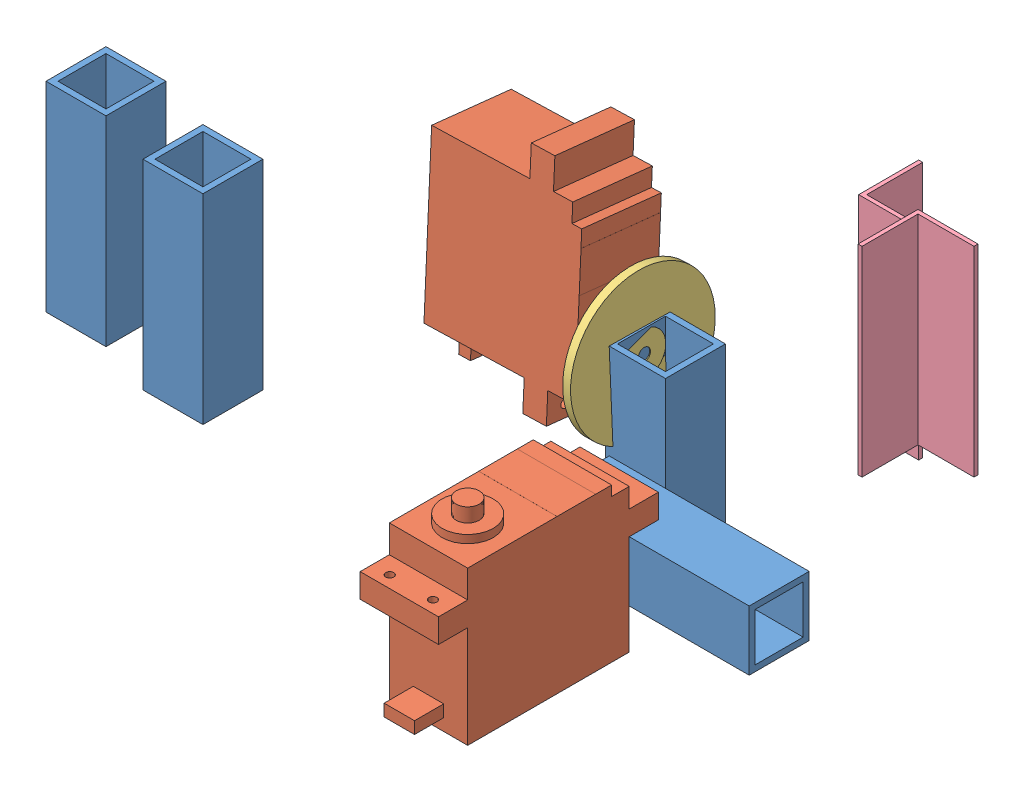
SolidWorks assembly 刀2, configuration ﾃﾞﾌｫﾙﾄ. Lengths in mm.
Overall size (157.88 100.48 102.11).
9 component instances, 4 part files, 4 mates.
Components (placement in the parent):
- 角_15_15_1.5-1: 角_15_15_1.5 [ﾃﾞﾌｫﾙﾄ] at (26.7735 11.274 48.4518) x (0 -1 0) z (-1 0 0) size (15 15 50)
- サーボ_MG995-1: サーボ_MG995 [ﾃﾞﾌｫﾙﾄ] at (12.6341 -6.7159 76.1612) x (-1 0 0) z (0 1 0) size (19.6 55 43.9)
- サーボ_MG995-2: サーボ_MG995 [ﾃﾞﾌｫﾙﾄ] at (-68.1766 42.576 5.5952) x (-0.019684 0.089439 0.995798) z (0.998898 0.044214 0.015775) size (19.6 55 43.9)
- サーボ_円盤-1: サーボ_円盤 [ﾃﾞﾌｫﾙﾄ] at (-25.1765 36.2069 32.7902) x (0.025317 -0.224419 -0.974164) z (0.998898 0.044214 0.015775) size (35.6 35.6 5.1)
- 角_15_15_1.5-2: 角_15_15_1.5 [ﾃﾞﾌｫﾙﾄ] at (-81.3631 24.7489 83.9472) x (-1 0 0) z (0 1 0) size (15 15 50)
- 角_15_15_1.5-3: 角_15_15_1.5 [ﾃﾞﾌｫﾙﾄ] at (-98.939 36.1769 90.6218) x (-1 0 0) z (0 1 0) size (15 15 50)
- L_15_15_1-1: L_15_15_1 [ﾃﾞﾌｫﾙﾄ] at (41.4173 92.2551 31.7871) x (1 0 0) z (0 -1 0) size (15 15 50)
- L_15_15_1-2: L_15_15_1 [ﾃﾞﾌｫﾙﾄ] at (20.2141 31.669 8.1315) x (1 0 0) z (0 1 0) size (15 15 50)
- 角_15_15_1.5-4: 角_15_15_1.5 [ﾃﾞﾌｫﾙﾄ] at (-17.4544 41.7772 33.1484) x (1 0 0) z (0 -1 0) size (15 15 50)
Mates (geometry in assembly coordinates):
- 一致1: coincident anti-aligned: plane of 角_15_15_1.5-1 through (-23.2265 18.2841 56.1844) normal (0 1 0); plane of サーボ_MG995-1 through (12.6341 18.2841 48.8844) normal (0 -1 0)
- 一致2: coincident anti-aligned: plane of 角_15_15_1.5-1 through (-23.2265 18.2841 56.1844) normal (0 0 1); plane of サーボ_MG995-1 through (-3.2305 29.1841 56.1844) normal (0 0 -1)
- 同心円1: concentric aligned: circle of サーボ_MG995-2; circle of サーボ_円盤-1
- 一致3: coincident anti-aligned: plane of サーボ_MG995-2 through (-27.8736 36.0875 32.7476) normal (0.998898 0.044214 0.015775); plane of サーボ_円盤-1 through (-27.8736 36.0875 32.7476) normal (-0.998898 -0.044214 -0.015775)
